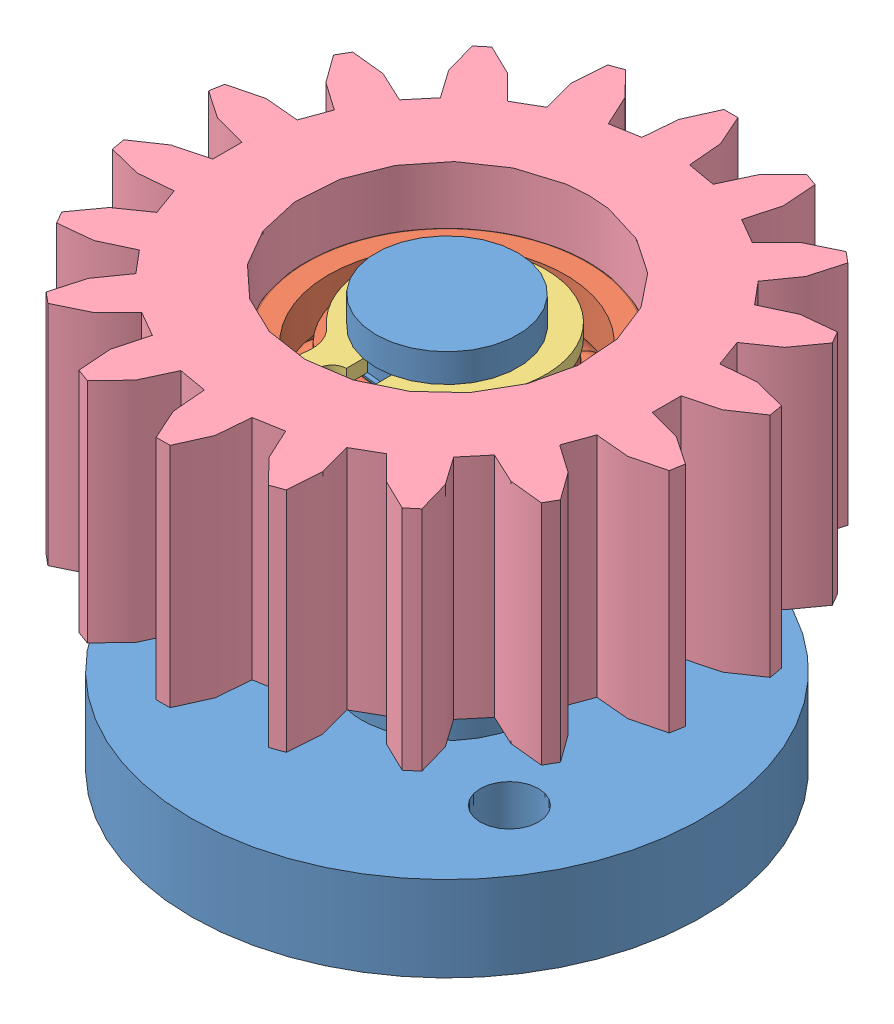
SolidWorks assembly 惰轮传动, configuration 默认. Lengths in mm.
Overall size (19.78 15 20).
4 component instances, 4 part files, 6 mates.
Components (placement in the parent):
- 惰轮轴-1: 惰轮轴 [默认] at (41.2103 -20.5095 -0.913) size (18 14.5 18)
- deep groove ball bearings gb-1: deep groove ball bearings gb [Rolling bearings 637-5 GB 276-94] at (41.2103 -12.5095 -0.913) x (0 -1 0) z (0.758451 0 -0.651731) size (4 10 10)
- circlips for shaft--type a small gb-2: circlips for shaft--type a small gb [GB_CONNECTING_PIECE_RING_RRA 5] at (41.2103 -10.0095 -1.193) x (1 0 0) z (0 1 0) size (6.4 8.28 0.5)
- spur gear_gb-3: spur gear_gb [GB - Spur gear 1M 18T 20PA 8FW ---S18A75H50L10.0N] at (41.2103 -8.5095 -0.913) x (0 -1 0) z (0 0 1) size (8 19.78 20)
Mates (geometry in assembly coordinates):
- 同心1: concentric anti-aligned: cylinder of 惰轮轴-1 through (41.2103 -9.0095 -0.913) axis (0 -1 0) radius 2.5; cylinder of deep groove ball bearings gb-1 through (41.2103 -5.5381 -0.913) axis (0 1 0) radius 2.5
- 重合1: coincident anti-aligned: plane of 惰轮轴-1 through (41.2103 -14.5095 -0.913) normal (0 1 0); plane of deep groove ball bearings gb-1 through (39.5809 -14.5095 -2.8091) normal (0 -1 0)
- 同心2: concentric aligned: cylinder of 惰轮轴-1 through (41.2103 -11.5095 -0.913) axis (0 1 0) radius 2.35; cylinder of circlips for shaft--type a small gb-2 through (41.2103 -10.5095 -0.913) axis (0 1 0) radius 2.35
- 重合2: coincident anti-aligned: plane of 惰轮轴-1 through (41.2103 -10.0095 1.437) normal (0 -1 0); plane of circlips for shaft--type a small gb-2 through (40.7103 -10.0095 2.6332) normal (0 1 0)
- 宽度1: width aligned: plane of spur gear_gb-3 through (41.2103 -8.5095 -0.913) normal (0 1 0); plane of spur gear_gb-3 through (41.2103 -16.5095 -0.913) normal (0 -1 0); plane of deep groove ball bearings gb-1 through (37.9516 -10.5095 -4.7052) normal (0 1 0); plane of deep groove ball bearings gb-1 through (37.9516 -14.5095 -4.7052) normal (0 -1 0)
- 同心3: concentric anti-aligned: cylinder of 惰轮轴-1 through (41.2103 -14.5095 -0.913) axis (0 -1 0) radius 3; cylinder of spur gear_gb-3 through (41.2103 -58.5096 -0.913) axis (0 1 0) radius 5
